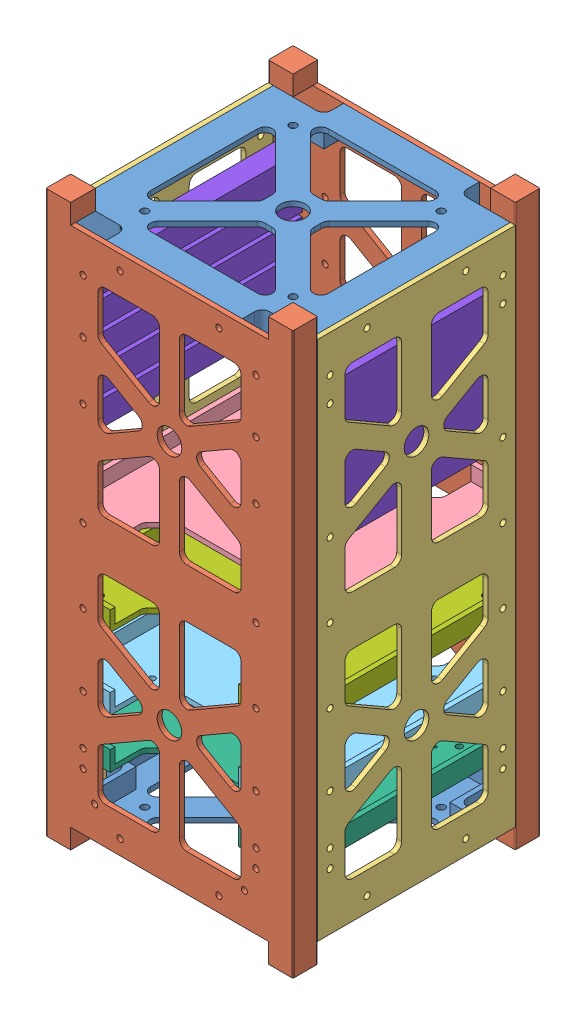
SolidWorks assembly STRUCTURES_BASE_ASSEMBLY, configuration Default. Lengths in mm.
Overall size (100 227 100).
12 component instances, 8 part files, 22 mates.
Components (placement in the parent):
- Z_FACE-1: Z_FACE [Default] at origin size (96 10 96)
- X_FACE-1: X_FACE [Default] at (4 0 0) size (100 227 10)
- X_FACE-2: X_FACE [Default] at (92 0 -96) x (-1 0 0) z (0 0 -1) size (100 227 10)
- Y_FACE-1: Y_FACE [Default] at (96 0 -4) x (0 0 -1) z (1 0 0) size (80 211 2)
- Y_FACE-2: Y_FACE [Default] at (-2 0 -4) x (0 0 -1) z (1 0 0) size (80 211 2)
- Z_FACE-2: Z_FACE [Default] at (0 211 0) x (0 0 -1) z (-1 0 0) size (96 10 96)
- BATTERY_MOUNTING_BRACKET-1: BATTERY_MOUNTING_BRACKET [Default] at (48 104.2 -48) x (0 0 -1) z (0 1 0) size (96 96 8)
- MRW_MOUNTING_BRACKET-1: MRW_MOUNTING_BRACKET [Default] at (48 45.2 -48) x (0 0 -1) z (0 1 0) size (96 96 8)
- STANDARD_MOUNTING_BRACKET_HDD-1: STANDARD_MOUNTING_BRACKET_HDD [Default] at (48 25.2 -48) x (0 0 -1) z (0 1 0) size (96 96 8)
- STANDARD_MOUNTING_BRACKET_COILS-2: STANDARD_MOUNTING_BRACKET_COILS [Default] at (48 74.2 -48) x (0 0 -1) z (0 1 0) size (96 96 8)
- PCB_SHELF-1: PCB_SHELF [Default] at (96 134.2 -4.75) x (-1 0 0) z (0 0 -1) size (8.5 56.8 86.5)
- PCB_SHELF-2: PCB_SHELF [Default] at (0 134.2 -91.25) size (8.5 56.8 86.5)
Mates (geometry in assembly coordinates):
- Coincident1: coincident anti-aligned: circle of Z_FACE-1; circle of X_FACE-1
- Coincident2: coincident anti-aligned: circle of Z_FACE-1; circle of X_FACE-1
- Coincident3: coincident anti-aligned: circle of Z_FACE-1; circle of X_FACE-2
- Coincident4: coincident anti-aligned: circle of Z_FACE-1; circle of X_FACE-2
- Coincident6: coincident anti-aligned: circle of Z_FACE-1; circle of Y_FACE-1
- Coincident7: coincident anti-aligned: circle of Z_FACE-1; circle of Y_FACE-1
- Coincident8: coincident anti-aligned: circle of Z_FACE-1; circle of Y_FACE-2
- Coincident9: coincident anti-aligned: circle of Z_FACE-1; circle of Y_FACE-2
- Coincident10: coincident anti-aligned: circle of X_FACE-1; circle of Z_FACE-2
- Coincident11: coincident anti-aligned: circle of X_FACE-1; circle of Z_FACE-2
- Coincident12: coincident anti-aligned: circle of Y_FACE-2; circle of BATTERY_MOUNTING_BRACKET-1
- Coincident13: coincident anti-aligned: circle of Y_FACE-2; circle of BATTERY_MOUNTING_BRACKET-1
- Concentric1: concentric anti-aligned: circle of Y_FACE-2; circle of MRW_MOUNTING_BRACKET-1
- Coincident14: coincident anti-aligned: circle of Y_FACE-2; circle of MRW_MOUNTING_BRACKET-1
- Coincident15: coincident anti-aligned: circle of Y_FACE-2; circle of STANDARD_MOUNTING_BRACKET_HDD-1
- Coincident16: coincident anti-aligned: circle of Y_FACE-2; circle of STANDARD_MOUNTING_BRACKET_HDD-1
- Coincident17: coincident anti-aligned: circle of Y_FACE-2; circle of STANDARD_MOUNTING_BRACKET_COILS-2
- Coincident18: coincident anti-aligned: circle of Y_FACE-2; circle of STANDARD_MOUNTING_BRACKET_COILS-2
- Coincident19: coincident: circle of Y_FACE-1; circle of PCB_SHELF-1
- Coincident21: coincident anti-aligned: circle of Y_FACE-1; circle of PCB_SHELF-1
- Coincident22: coincident: cylinder of Y_FACE-2 through (0 186 -13) axis (1 0 0) radius 1.25; circle of PCB_SHELF-2
- Coincident23: coincident anti-aligned: circle of Y_FACE-2; circle of PCB_SHELF-2
